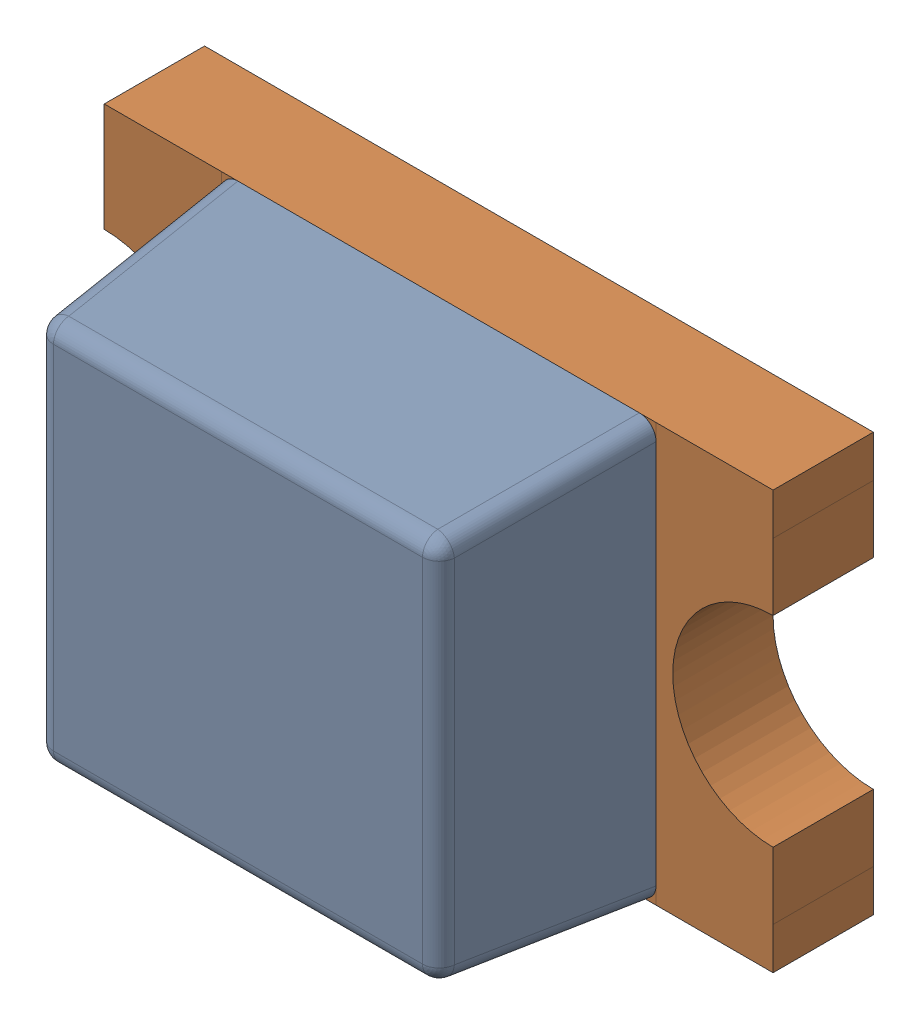
SolidWorks assembly D5_1.step, configuration Default. Lengths in mm.
Overall size (2 1.25 0.9).
2 component instances, 2 part files, 0 mates.
Components (placement in the parent):
- LED 0805 Lens RED_1.step-3: LED 0805 Lens RED_1.step [Default] at (470.1881 335.28 0) x (1 0 0) z (0 -1 0) size (1.3 0.6 1.25)
- LED 0805 Base RED_1.step-3: LED 0805 Base RED_1.step [Default] at (470.1881 335.28 0) x (1 0 0) z (0 -1 0) size (2 0.4 1.25)
